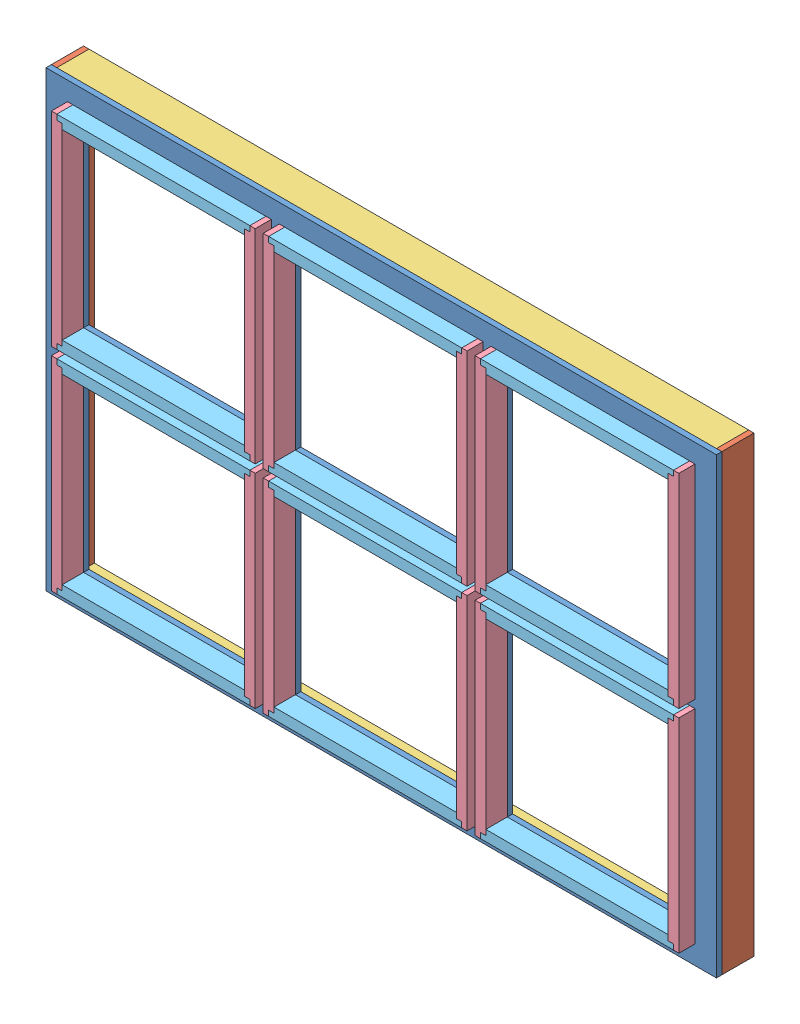
SolidWorks assembly World_Map_Assembly, configuration Default. Lengths in mm.
Overall size (1250 845 100).
29 component instances, 5 part files, 88 mates.
Components (placement in the parent):
- Backplate-1: Backplate [Default] x (-1 0 0) z (0 0 -1) size (1250 845 20)
- Big_Sides-1: Big_Sides [Default] at (-625 0 -40) x (0 0 -1) z (1 0 0) size (60 845 20)
- Big_Sides-2: Big_Sides [Default] at (625 0 -40) x (0 0 -1) z (-1 0 0) size (60 845 20)
- Big_Top_and_Bottom-1: Big_Top_and_Bottom [Default] at (0 422.5 -40) x (0 0 -1) z (0 -1 0) size (60 1230 20)
- Big_Top_and_Bottom-2: Big_Top_and_Bottom [Default] at (0 -422.5 -40) x (0 0 -1) z (0 1 0) size (60 1230 20)
- Small_Sides-1: Small_Sides [Default] at (-565 197.5 10) x (0 0 1) z (-1 0 0) size (40 380 20)
- Small_Sides-2: Small_Sides [Default] at (-565 -197.5 10) x (0 0 1) z (-1 0 0) size (40 380 20)
- Small_Sides-3: Small_Sides [Default] at (-225 197.5 10) x (0 0 1) z (1 0 0) size (40 380 20)
- Small_Sides-4: Small_Sides [Default] at (-225 -197.5 10) x (0 0 1) z (1 0 0) size (40 380 20)
- Small_Sides-5: Small_Sides [Default] at (-170 197.5 10) x (0 0 1) z (-1 0 0) size (40 380 20)
- Small_Sides-6: Small_Sides [Default] at (170 197.5 10) x (0 0 1) z (1 0 0) size (40 380 20)
- Small_Sides-7: Small_Sides [Default] at (225 197.5 10) x (0 0 1) z (-1 0 0) size (40 380 20)
- Small_Sides-8: Small_Sides [Default] at (565 197.5 10) x (0 0 1) z (1 0 0) size (40 380 20)
- Small_Sides-9: Small_Sides [Default] at (-170 -197.5 10) x (0 0 1) z (-1 0 0) size (40 380 20)
- Small_Sides-10: Small_Sides [Default] at (170 -197.5 10) x (0 0 1) z (1 0 0) size (40 380 20)
- Small_Sides-11: Small_Sides [Default] at (565 -197.5 10) x (0 0 1) z (1 0 0) size (40 380 20)
- Small_Sides-12: Small_Sides [Default] at (225 -197.5 10) x (0 0 1) z (-1 0 0) size (40 380 20)
- Small_Tops_and_Bottoms-1: Small_Tops_and_Bottoms [Default] at (-395 367.5 10) x (0 0 1) z (0 1 0) size (40 360 20)
- Small_Tops_and_Bottoms-2: Small_Tops_and_Bottoms [Default] at (-395 27.5 10) x (0 0 1) z (0 -1 0) size (40 360 20)
- Small_Tops_and_Bottoms-3: Small_Tops_and_Bottoms [Default] at (0 367.5 10) x (0 0 1) z (0 1 0) size (40 360 20)
- Small_Tops_and_Bottoms-4: Small_Tops_and_Bottoms [Default] at (395 367.5 10) x (0 0 1) z (0 1 0) size (40 360 20)
- Small_Tops_and_Bottoms-5: Small_Tops_and_Bottoms [Default] at (395 -27.5 10) x (0 0 1) z (0 1 0) size (40 360 20)
- Small_Tops_and_Bottoms-6: Small_Tops_and_Bottoms [Default] at (-395 -27.5 10) x (0 0 1) z (0 1 0) size (40 360 20)
- Small_Tops_and_Bottoms-7: Small_Tops_and_Bottoms [Default] at (0 -27.5 10) x (0 0 1) z (0 1 0) size (40 360 20)
- Small_Tops_and_Bottoms-8: Small_Tops_and_Bottoms [Default] at (0 27.5 10) x (0 0 1) z (0 -1 0) size (40 360 20)
- Small_Tops_and_Bottoms-9: Small_Tops_and_Bottoms [Default] at (395 27.5 10) x (0 0 1) z (0 -1 0) size (40 360 20)
- Small_Tops_and_Bottoms-10: Small_Tops_and_Bottoms [Default] at (-395 -367.5 10) x (0 0 1) z (0 -1 0) size (40 360 20)
- Small_Tops_and_Bottoms-11: Small_Tops_and_Bottoms [Default] at (0 -367.5 10) x (0 0 1) z (0 -1 0) size (40 360 20)
- Small_Tops_and_Bottoms-12: Small_Tops_and_Bottoms [Default] at (395 -367.5 10) x (0 0 1) z (0 -1 0) size (40 360 20)
Mates (geometry in assembly coordinates):
- Coincident8: coincident: point of Backplate-1
- Coincident9: coincident anti-aligned: plane of Backplate-1 through (0 0 0) normal (0 0 -1)
- Coincident10: coincident aligned: plane of Backplate-1 through (0 0 0) normal (0 1 0)
- Coincident11: coincident anti-aligned: plane of Backplate-1 through (0 0 0) normal (-1 0 0)
- Coincident12: coincident aligned: plane of Backplate-1 through (625 422.5 -20) normal (1 0 0); plane of Big_Sides-2 through (625 0 -40) normal (1 0 0)
- Coincident13: coincident anti-aligned: plane of Backplate-1 through (0 0 -10) normal (0 0 -1); plane of Big_Sides-2 through (605 422.5 -10) normal (0 0 1)
- Coincident14: coincident aligned: plane of Backplate-1 through (-615 412.5 -10) normal (0 1 0); plane of Big_Sides-2 through (615 412.5 -20) normal (0 1 0)
- Coincident15: coincident aligned: plane of Big_Sides-1 through (-605 422.5 -10) normal (0 1 0); plane of Big_Sides-2 through (605 422.5 -70) normal (0 1 0)
- Coincident16: coincident aligned: plane of Backplate-1 through (-625 -422.5 -20) normal (-1 0 0); plane of Big_Sides-1 through (-625 0 -40) normal (-1 0 0)
- Coincident17: coincident anti-aligned: plane of Backplate-1 through (0 0 -10) normal (0 0 -1); plane of Big_Sides-1 through (-605 -422.5 -10) normal (0 0 1)
- Coincident18: coincident aligned: plane of Backplate-1 through (-625 422.5 -20) normal (0 1 0); plane of Big_Top_and_Bottom-1 through (0 422.5 -40) normal (0 1 0)
- Coincident19: coincident anti-aligned: plane of Backplate-1 through (0 0 -10) normal (0 0 -1); plane of Big_Top_and_Bottom-1 through (-615 402.5 -10) normal (0 0 1)
- Coincident20: coincident anti-aligned: plane of Big_Sides-2 through (615 0 -40) normal (-1 0 0); plane of Big_Top_and_Bottom-1 through (615 402.5 -10) normal (1 0 0)
- Coincident21: coincident aligned: plane of Backplate-1 through (625 -422.5 -20) normal (0 -1 0); plane of Big_Top_and_Bottom-2 through (0 -422.5 -40) normal (0 -1 0)
- Coincident22: coincident anti-aligned: plane of Backplate-1 through (0 0 -10) normal (0 0 -1); plane of Big_Top_and_Bottom-2 through (615 -402.5 -10) normal (0 0 1)
- Coincident23: coincident anti-aligned: plane of Big_Sides-2 through (615 0 -40) normal (-1 0 0); plane of Big_Top_and_Bottom-2 through (615 -402.5 -70) normal (1 0 0)
- Coincident25: coincident anti-aligned: plane of Backplate-1 through (0 0 0) normal (0 0 1); plane of Small_Sides-1 through (-575 387.5 0) normal (0 0 -1)
- Coincident26: coincident anti-aligned: plane of Backplate-1 through (0 377.5 -10) normal (0 -1 0); plane of Small_Sides-1 through (-575 377.5 30) normal (0 1 0)
- Coincident27: coincident anti-aligned: plane of Backplate-1 through (-575 0 -10) normal (1 0 0); plane of Small_Sides-1 through (-575 197.5 10) normal (-1 0 0)
- Coincident29: coincident anti-aligned: plane of Backplate-1 through (0 0 -10) normal (0 0 1); plane of Small_Sides-2 through (-585 -387.5 -10) normal (0 0 -1)
- Coincident30: coincident anti-aligned: plane of Backplate-1 through (0 -17.5 -10) normal (0 -1 0); plane of Small_Sides-2 through (-575 -17.5 30) normal (0 1 0)
- Coincident31: coincident anti-aligned: plane of Backplate-1 through (-575 0 -10) normal (1 0 0); plane of Small_Sides-2 through (-575 -197.5 10) normal (-1 0 0)
- Coincident32: coincident aligned: plane of Small_Sides-1 through (-585 387.5 30) normal (0 0 1); plane of Small_Sides-3 through (-205 7.5 30) normal (0 0 1)
- Coincident33: coincident aligned: plane of Small_Sides-1 through (-585 7.5 30) normal (0 -1 0); plane of Small_Sides-3 through (-205 7.5 -10) normal (0 -1 0)
- Coincident34: coincident anti-aligned: plane of Backplate-1 through (-215 0 -10) normal (-1 0 0); plane of Small_Sides-3 through (-215 197.5 10) normal (1 0 0)
- Coincident35: coincident aligned: plane of Small_Sides-3 through (-205 7.5 30) normal (0 0 1); plane of Small_Sides-5 through (-190 387.5 30) normal (0 0 1)
- Coincident36: coincident anti-aligned: plane of Backplate-1 through (-180 0 -10) normal (1 0 0); plane of Small_Sides-5 through (-180 197.5 10) normal (-1 0 0)
- Coincident37: coincident aligned: plane of Small_Sides-3 through (-205 7.5 -10) normal (0 -1 0); plane of Small_Sides-5 through (-190 7.5 30) normal (0 -1 0)
- Coincident38: coincident aligned: plane of Small_Sides-3 through (-205 7.5 30) normal (0 0 1); plane of Small_Sides-4 through (-205 -387.5 30) normal (0 0 1)
- Coincident39: coincident aligned: plane of Small_Sides-3 through (-205 197.5 10) normal (1 0 0); plane of Small_Sides-4 through (-205 -197.5 10) normal (1 0 0)
- Coincident40: coincident aligned: plane of Small_Sides-2 through (-585 -387.5 30) normal (0 -1 0); plane of Small_Sides-4 through (-205 -387.5 -10) normal (0 -1 0)
- Coincident41: coincident aligned: plane of Small_Sides-5 through (-190 387.5 30) normal (0 0 1); plane of Small_Sides-9 through (-190 -7.5 30) normal (0 0 1)
- Coincident42: coincident aligned: plane of Small_Sides-5 through (-190 197.5 10) normal (-1 0 0); plane of Small_Sides-9 through (-190 -197.5 10) normal (-1 0 0)
- Coincident43: coincident aligned: plane of Small_Sides-2 through (-585 -387.5 30) normal (0 -1 0); plane of Small_Sides-9 through (-190 -387.5 30) normal (0 -1 0)
- Coincident44: coincident aligned: plane of Small_Sides-9 through (-190 -7.5 30) normal (0 0 1); plane of Small_Sides-10 through (190 -387.5 30) normal (0 0 1)
- Coincident45: coincident aligned: plane of Small_Sides-10 through (190 -387.5 -10) normal (0 -1 0); plane of Small_Sides-4 through (-205 -387.5 -10) normal (0 -1 0)
- Coincident46: coincident anti-aligned: plane of Backplate-1 through (180 0 -10) normal (-1 0 0); plane of Small_Sides-10 through (180 -197.5 10) normal (1 0 0)
- Coincident47: coincident aligned: plane of Small_Sides-10 through (190 -387.5 30) normal (0 0 1); plane of Small_Sides-11 through (585 -387.5 30) normal (0 0 1)
- Coincident48: coincident aligned: plane of Small_Sides-10 through (190 -387.5 -10) normal (0 -1 0); plane of Small_Sides-11 through (585 -387.5 -10) normal (0 -1 0)
- Coincident49: coincident anti-aligned: plane of Backplate-1 through (575 0 -10) normal (-1 0 0); plane of Small_Sides-11 through (575 -197.5 10) normal (1 0 0)
- Coincident50: coincident aligned: plane of Small_Sides-10 through (190 -387.5 30) normal (0 0 1); plane of Small_Sides-12 through (205 -7.5 30) normal (0 0 1)
- Coincident51: coincident aligned: plane of Small_Sides-10 through (190 -7.5 30) normal (0 1 0); plane of Small_Sides-12 through (205 -7.5 -10) normal (0 1 0)
- Coincident52: coincident anti-aligned: plane of Backplate-1 through (215 0 -10) normal (1 0 0); plane of Small_Sides-12 through (215 -197.5 10) normal (-1 0 0)
- Coincident53: coincident aligned: plane of Small_Sides-6 through (190 7.5 30) normal (0 0 1); plane of Small_Sides-10 through (190 -387.5 30) normal (0 0 1)
- Coincident54: coincident aligned: plane of Small_Sides-5 through (-190 7.5 30) normal (0 -1 0); plane of Small_Sides-6 through (190 7.5 -10) normal (0 -1 0)
- Coincident55: coincident aligned: plane of Small_Sides-6 through (190 197.5 10) normal (1 0 0); plane of Small_Sides-10 through (190 -197.5 10) normal (1 0 0)
- Coincident56: coincident aligned: plane of Small_Sides-6 through (190 7.5 30) normal (0 0 1); plane of Small_Sides-7 through (205 387.5 30) normal (0 0 1)
- Coincident57: coincident aligned: plane of Small_Sides-6 through (190 7.5 -10) normal (0 -1 0); plane of Small_Sides-7 through (205 7.5 30) normal (0 -1 0)
- Coincident58: coincident aligned: plane of Small_Sides-7 through (225 197.5 10) normal (1 0 0); plane of Small_Sides-12 through (225 -197.5 10) normal (1 0 0)
- Coincident59: coincident aligned: plane of Small_Sides-8 through (585 7.5 30) normal (0 0 1); plane of Small_Sides-11 through (585 -387.5 30) normal (0 0 1)
- Coincident60: coincident aligned: plane of Small_Sides-8 through (585 197.5 10) normal (1 0 0); plane of Small_Sides-11 through (585 -197.5 10) normal (1 0 0)
- Coincident61: coincident aligned: plane of Small_Sides-7 through (205 387.5 -10) normal (0 1 0); plane of Small_Sides-8 through (585 387.5 30) normal (0 1 0)
- Coincident62: coincident anti-aligned: plane of Small_Sides-3 through (-215 377.5 -10) normal (0 1 0); plane of Small_Tops_and_Bottoms-1 through (-395 377.5 10) normal (0 -1 0)
- Coincident63: coincident aligned: plane of Small_Sides-3 through (-205 7.5 30) normal (0 0 1); plane of Small_Tops_and_Bottoms-1 through (-215 387.5 30) normal (0 0 1)
- Coincident64: coincident anti-aligned: plane of Small_Sides-3 through (-225 197.5 10) normal (-1 0 0); plane of Small_Tops_and_Bottoms-1 through (-225 377.5 30) normal (1 0 0)
- Coincident65: coincident aligned: plane of Small_Sides-1 through (-585 387.5 30) normal (0 0 1); plane of Small_Tops_and_Bottoms-2 through (-575 7.5 30) normal (0 0 1)
- Coincident66: coincident anti-aligned: plane of Small_Sides-3 through (-215 197.5 10) normal (-1 0 0); plane of Small_Tops_and_Bottoms-2 through (-215 7.5 30) normal (1 0 0)
- Coincident67: coincident aligned: plane of Small_Sides-1 through (-585 7.5 30) normal (0 -1 0); plane of Small_Tops_and_Bottoms-2 through (-395 7.5 10) normal (0 -1 0)
- Coincident68: coincident aligned: plane of Small_Tops_and_Bottoms-1 through (-215 387.5 30) normal (0 0 1); plane of Small_Tops_and_Bottoms-3 through (180 387.5 30) normal (0 0 1)
- Coincident69: coincident anti-aligned: plane of Small_Sides-6 through (180 197.5 10) normal (-1 0 0); plane of Small_Tops_and_Bottoms-3 through (180 387.5 -10) normal (1 0 0)
- Coincident70: coincident aligned: plane of Small_Sides-6 through (190 387.5 30) normal (0 1 0); plane of Small_Tops_and_Bottoms-3 through (0 387.5 10) normal (0 1 0)
- Coincident71: coincident anti-aligned: plane of Small_Sides-7 through (215 197.5 10) normal (1 0 0); plane of Small_Tops_and_Bottoms-4 through (215 387.5 30) normal (-1 0 0)
- Coincident72: coincident aligned: plane of Small_Sides-7 through (205 387.5 30) normal (0 0 1); plane of Small_Tops_and_Bottoms-4 through (575 387.5 30) normal (0 0 1)
- Coincident73: coincident aligned: plane of Small_Tops_and_Bottoms-3 through (0 387.5 10) normal (0 1 0); plane of Small_Tops_and_Bottoms-4 through (395 387.5 10) normal (0 1 0)
- Coincident74: coincident aligned: plane of Small_Sides-8 through (585 7.5 30) normal (0 0 1); plane of Small_Tops_and_Bottoms-9 through (215 7.5 30) normal (0 0 1)
- Coincident75: coincident anti-aligned: plane of Small_Sides-8 through (575 197.5 10) normal (-1 0 0); plane of Small_Tops_and_Bottoms-9 through (575 7.5 30) normal (1 0 0)
- Coincident76: coincident aligned: plane of Small_Sides-8 through (585 7.5 -10) normal (0 -1 0); plane of Small_Tops_and_Bottoms-9 through (395 7.5 10) normal (0 -1 0)
- Coincident77: coincident anti-aligned: plane of Small_Sides-6 through (180 197.5 10) normal (-1 0 0); plane of Small_Tops_and_Bottoms-8 through (180 7.5 30) normal (1 0 0)
- Coincident78: coincident aligned: plane of Small_Tops_and_Bottoms-8 through (0 7.5 10) normal (0 -1 0); plane of Small_Tops_and_Bottoms-9 through (395 7.5 10) normal (0 -1 0)
- Coincident79: coincident aligned: plane of Small_Sides-6 through (190 7.5 30) normal (0 0 1); plane of Small_Tops_and_Bottoms-8 through (-180 7.5 30) normal (0 0 1)
- Coincident80: coincident aligned: plane of Small_Sides-2 through (-585 -7.5 30) normal (0 0 1); plane of Small_Tops_and_Bottoms-6 through (-215 -7.5 30) normal (0 0 1)
- Coincident81: coincident anti-aligned: plane of Small_Sides-4 through (-215 -197.5 10) normal (-1 0 0); plane of Small_Tops_and_Bottoms-6 through (-215 -7.5 -10) normal (1 0 0)
- Coincident82: coincident aligned: plane of Small_Sides-4 through (-205 -7.5 30) normal (0 1 0); plane of Small_Tops_and_Bottoms-6 through (-395 -7.5 10) normal (0 1 0)
- Coincident83: coincident anti-aligned: plane of Small_Sides-9 through (-180 -197.5 10) normal (1 0 0); plane of Small_Tops_and_Bottoms-7 through (-180 -7.5 30) normal (-1 0 0)
- Coincident84: coincident aligned: plane of Small_Sides-9 through (-190 -7.5 30) normal (0 0 1); plane of Small_Tops_and_Bottoms-7 through (180 -7.5 30) normal (0 0 1)
- Coincident85: coincident aligned: plane of Small_Tops_and_Bottoms-6 through (-395 -7.5 10) normal (0 1 0); plane of Small_Tops_and_Bottoms-7 through (0 -7.5 10) normal (0 1 0)
- Coincident86: coincident anti-aligned: plane of Small_Sides-12 through (215 -197.5 10) normal (1 0 0); plane of Small_Tops_and_Bottoms-5 through (215 -7.5 30) normal (-1 0 0)
- Coincident87: coincident aligned: plane of Small_Tops_and_Bottoms-5 through (395 -7.5 10) normal (0 1 0); plane of Small_Tops_and_Bottoms-7 through (0 -7.5 10) normal (0 1 0)
- Coincident88: coincident aligned: plane of Small_Sides-12 through (205 -7.5 30) normal (0 0 1); plane of Small_Tops_and_Bottoms-5 through (575 -7.5 30) normal (0 0 1)
- Coincident89: coincident aligned: plane of Small_Sides-11 through (585 -387.5 30) normal (0 0 1); plane of Small_Tops_and_Bottoms-12 through (215 -387.5 30) normal (0 0 1)
- Coincident90: coincident anti-aligned: plane of Small_Sides-12 through (215 -197.5 10) normal (1 0 0); plane of Small_Tops_and_Bottoms-12 through (215 -387.5 -10) normal (-1 0 0)
- Coincident91: coincident aligned: plane of Small_Sides-12 through (205 -387.5 30) normal (0 -1 0); plane of Small_Tops_and_Bottoms-12 through (395 -387.5 10) normal (0 -1 0)
- Coincident92: coincident aligned: plane of Small_Sides-10 through (190 -387.5 30) normal (0 0 1); plane of Small_Tops_and_Bottoms-11 through (-180 -387.5 30) normal (0 0 1)
- Coincident93: coincident anti-aligned: plane of Small_Sides-10 through (180 -197.5 10) normal (-1 0 0); plane of Small_Tops_and_Bottoms-11 through (180 -387.5 30) normal (1 0 0)
- Coincident94: coincident aligned: plane of Small_Sides-10 through (190 -387.5 -10) normal (0 -1 0); plane of Small_Tops_and_Bottoms-11 through (0 -387.5 10) normal (0 -1 0)
- Coincident95: coincident aligned: plane of Small_Sides-2 through (-585 -387.5 30) normal (0 -1 0); plane of Small_Tops_and_Bottoms-10 through (-395 -387.5 10) normal (0 -1 0)
- Coincident96: coincident aligned: plane of Small_Sides-2 through (-585 -7.5 30) normal (0 0 1); plane of Small_Tops_and_Bottoms-10 through (-575 -387.5 30) normal (0 0 1)
- Coincident97: coincident anti-aligned: plane of Small_Sides-4 through (-215 -197.5 10) normal (-1 0 0); plane of Small_Tops_and_Bottoms-10 through (-215 -387.5 30) normal (1 0 0)
